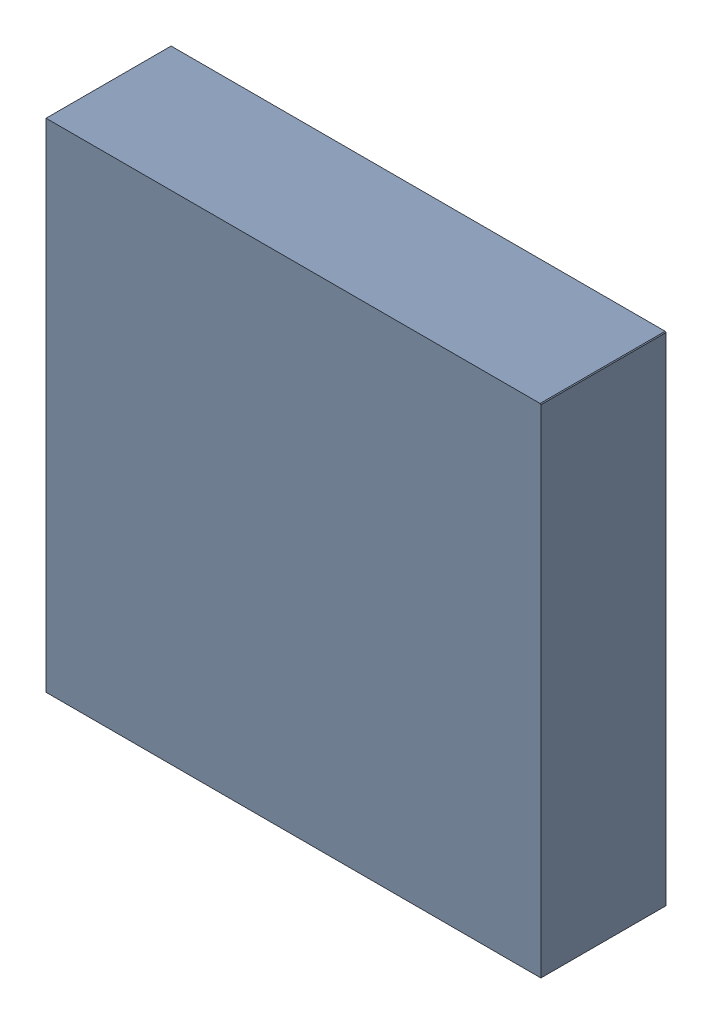
SolidWorks assembly U5, configuration ﾃﾞﾌｫﾙﾄ. Lengths in mm.
Overall size (3.17 3.19 0.82).
4 component instances, 2 part files, 0 mates.
Components (placement in the parent):
- 6641442208-1: 6641442208 [ﾃﾞﾌｫﾙﾄ] at (8.4975 4.6 -2.7339) size (3.17 3.19 0.81)
  - Extruded-19-1: Extruded-19 [ﾃﾞﾌｫﾙﾄ] at origin size (3.17 3.19 0.81)
- 6641441808-1: 6641441808 [ﾃﾞﾌｫﾙﾄ] at (7.1852 5.8608 -2.7339) x (0 -1 0) z (0 0 -1) size (0.2 0.2 0.01)
  - Cylinder-20-1: Cylinder-20 [ﾃﾞﾌｫﾙﾄ] at origin size (0.2 0.2 0.01)
